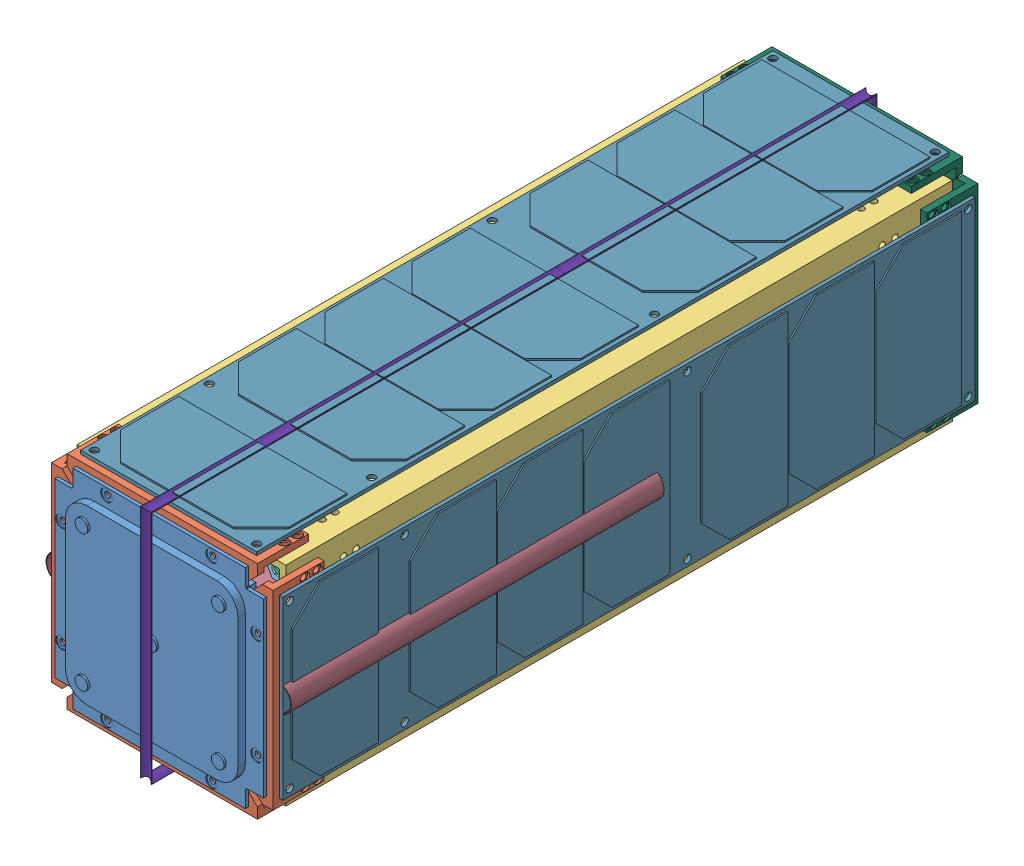
SolidWorks assembly RADIO3, configuration Default. Lengths in mm.
Overall size (115.59 110.69 340.69).
76 component instances, 17 part files, 142 mates.
Components (placement in the parent):
- Nanocom Antenna-1: Nanocom Antenna [Default] at (54.7327 27.087 80.9297) size (98 98 11)
- Top Sipport-1: Top Sipport [Default] at (83.9034 50.4516 80.9297) x (0 -1 0) z (0 0 -1) size (89.4 11 24)
- Top Sipport-2: Top Sipport [Default] at (-15.8818 37.5538 80.9297) x (0 1 0) z (0 0 -1) size (89.4 11 24)
- Top Sipport-3: Top Sipport [Default] at (27.5619 93.8953 80.9297) x (1 0 0) z (0 0 -1) size (89.4 11 24)
- Top Sipport-4: Top Sipport [Default] at (40.4598 -5.8899 80.9297) x (-1 0 0) z (0 0 -1) size (89.4 11 24)
- Support-1: Support [Default] at (-14.9892 90.3455 -221.7132) x (0 -1 0) z (1 0 0) size (18 313 15)
- Support-2: Support [Default] at (-12.332 -4.9973 -221.7132) x (1 0 0) z (0 1 0) size (18 313 15)
- Support-3: Support [Default] at (80.3537 93.0027 -221.7132) x (-1 0 0) z (0 -1 0) size (18 313 15)
- Support-4: Support [Default] at (83.0108 -2.3402 -221.7132) x (0 1 0) z (-1 0 0) size (18 313 15)
- Top Plate2-1: Top Plate2 [Default] at (13.317 21.6849 56.9297) x (-1 0 0) z (0 0 -1) size (92 92 23)
- Nut-1: Nut [Default] at (-1.4892 79.5027 56.9297) size (11.55 10 5.32)
- Nut-2: Nut [Default] at (69.5108 8.5027 56.9297) x (0.821931 0.569587 0) z (0 0 1) size (11.55 10 5.32)
- Nut-3: Nut [Default] at (69.5108 79.5027 56.9297) size (11.55 10 5.32)
- Nut-4: Nut [Default] at (-1.4892 8.5027 56.9297) size (11.55 10 5.32)
- Threaded Rod2-1: Threaded Rod2 [Default] at (69.5108 8.5027 -231.0703) size (6.4 7.01 294.26)
- Threaded Rod2-2: Threaded Rod2 [Default] at (-1.4892 8.5027 -231.0703) size (6.4 7.01 294.26)
- Threaded Rod2-3: Threaded Rod2 [Default] at (-1.4892 79.5027 -231.0703) size (6.4 7.01 294.26)
- Threaded Rod2-4: Threaded Rod2 [Default] at (69.5108 79.5027 -231.0703) size (6.4 7.01 294.26)
- Mid Plate-1: Mid Plate [Default] at (4.649 54.0261 25.9297) size (86 86 3)
- Nut-5: Nut [Default] at (-1.4892 8.5027 20.9297) x (0.999286 -0.037791 0) z (0 0 1) size (11.55 10 5.32)
- Nut-6: Nut [Default] at (-1.4892 8.5027 28.9297) size (11.55 10 5.32)
- Nut-7: Nut [Default] at (69.5108 8.5027 28.9297) size (11.55 10 5.32)
- Nut-8: Nut [Default] at (69.5108 8.5027 20.9297) x (0.921379 0.388666 0) z (0 0 1) size (11.55 10 5.32)
- Nut-9: Nut [Default] at (69.5108 79.5027 28.9297) size (11.55 10 5.32)
- Nut-10: Nut [Default] at (-1.4892 79.5027 28.9297) size (11.55 10 5.32)
- Nut-11: Nut [Default] at (69.5108 79.5027 20.9297) x (0.963517 0.267648 0) z (0 0 1) size (11.55 10 5.32)
- Nut-12: Nut [Default] at (-1.4892 79.5027 20.9297) x (0.997929 0.06432 0) z (0 0 1) size (11.55 10 5.32)
- SDR-1: SDR [Default] at (37.1692 34.198 30.9297) size (65 40 16.8)
- TTC Radio-1: TTC Radio [Default] at (48.3672 78.5027 28.9297) x (0 1 0) z (0 0 1) size (19.7 16 5)
- Raspberry Pi-1: Raspberry Pi [Default] at (63.5108 49.6464 -55.0703) size (66 30.48 5)
- TTC Circuit-1: TTC Circuit [Default] at (24.4431 25.9578 10.9297) size (80 50 10)
- Battery-1: Battery [Default] at (21.7415 31.358 -37.0703) size (70.1 42.59 38.1)
- Tape Antenna-3: Tape Antenna [Default] at (-17.3053 44.2096 -97.0703) x (-0.035253 -0.999378 0) z (0 0 1) size (11.67 4.21 175)
- Tape Antenna-4: Tape Antenna [Default] at (85.299 43.4652 -97.0703) x (0.030207 0.999544 0) z (0 0 1) size (11.67 4.21 175)
- Mid Plate-2: Mid Plate [Default] at (4.649 54.0261 7.9297) size (86 86 3)
- Nut-13: Nut [Default] at (-1.4892 8.5027 10.9297) size (11.55 10 5.32)
- Nut-14: Nut [Default] at (69.5108 79.5027 10.9297) size (11.55 10 5.32)
- Nut-15: Nut [Default] at (-1.4892 8.5027 2.9297) size (11.55 10 5.32)
- Nut-16: Nut [Default] at (-1.4892 79.5027 10.9297) size (11.55 10 5.32)
- Nut-17: Nut [Default] at (-1.4892 79.5027 2.9297) size (11.55 10 5.32)
- Nut-18: Nut [Default] at (69.5108 8.5027 2.9297) size (11.55 10 5.32)
- Nut-19: Nut [Default] at (69.5108 8.5027 10.9297) size (11.55 10 5.32)
- Nut-20: Nut [Default] at (69.5108 79.5027 2.9297) size (11.55 10 5.32)
- Mid Plate-3: Mid Plate [Default] at (4.649 54.0261 -40.0703) size (86 86 3)
- Nut-21: Nut [Default] at (69.5108 79.5027 -37.0703) size (11.55 10 5.32)
- Nut-22: Nut [Default] at (-1.4892 8.5027 -40.0703) x (-0.923728 -0.383049 0) z (0 0 -1) size (11.55 10 5.32)
- Nut-23: Nut [Default] at (-1.4892 79.5027 -40.0703) x (-0.923728 -0.383049 0) z (0 0 -1) size (11.55 10 5.32)
- Nut-24: Nut [Default] at (69.5108 8.5027 -37.0703) size (11.55 10 5.32)
- Nut-25: Nut [Default] at (69.5108 79.5027 -40.0703) x (-0.923728 -0.383049 0) z (0 0 -1) size (11.55 10 5.32)
- Nut-26: Nut [Default] at (69.5108 8.5027 -40.0703) x (-0.923728 -0.383049 0) z (0 0 -1) size (11.55 10 5.32)
- Nut-27: Nut [Default] at (-1.4892 8.5027 -37.0703) size (11.55 10 5.32)
- Nut-28: Nut [Default] at (-1.4892 79.5027 -37.0703) size (11.55 10 5.32)
- Nut-29: Nut [Default] at (-1.4892 8.5027 -63.0703) size (11.55 10 5.32)
- Nut-30: Nut [Default] at (69.5108 79.5027 -63.0703) size (11.55 10 5.32)
- Nut-31: Nut [Default] at (69.5108 8.5027 -63.0703) size (11.55 10 5.32)
- Nut-32: Nut [Default] at (-1.4892 8.5027 -55.0703) size (11.55 10 5.32)
- Nut-33: Nut [Default] at (-1.4892 79.5027 -55.0703) size (11.55 10 5.32)
- Nut-34: Nut [Default] at (69.5108 8.5027 -55.0703) size (11.55 10 5.32)
- Nut-35: Nut [Default] at (-1.4892 79.5027 -63.0703) size (11.55 10 5.32)
- Nut-36: Nut [Default] at (69.5108 79.5027 -55.0703) size (11.55 10 5.32)
- Mid Plate-4: Mid Plate [Default] at (4.649 54.0261 -58.0703) size (86 86 3)
- Top Plate2-2: Top Plate2 [Default] at (54.7047 21.6849 -226.0703) size (92 92 23)
- Nut-37: Nut [Default] at (69.5108 8.5027 -226.0703) x (-0.923728 -0.383049 0) z (0 0 -1) size (11.55 10 5.32)
- Nut-38: Nut [Default] at (69.5108 79.5027 -226.0703) x (-0.923728 -0.383049 0) z (0 0 -1) size (11.55 10 5.32)
- Nut-39: Nut [Default] at (-1.4892 8.5027 -226.0703) x (-0.923728 -0.383049 0) z (0 0 -1) size (11.55 10 5.32)
- Nut-40: Nut [Default] at (-1.4892 79.5027 -226.0703) x (-0.923728 -0.383049 0) z (0 0 -1) size (11.55 10 5.32)
- 3U Panel-1: 3U Panel [Default] at (-17.9892 -8.6653 1.9441) x (0 -1 0) z (-1 0 0) size (82.6 325 2.3)
- 3U Panel-5: 3U Panel [Default] at (86.6788 -7.9973 1.9441) x (1 0 0) z (0 -1 0) size (82.6 325 2.3)
- 3U Panel-6: 3U Panel [Default] at (86.0108 96.6707 1.9441) x (0 1 0) z (1 0 0) size (82.6 325 2.3)
- 3U Panel-7: 3U Panel [Default] at (-18.6571 96.0027 1.9441) x (-1 0 0) z (0 1 0) size (82.6 325 2.3)
- Top Support Solar Panel-1: Top Support Solar Panel [Default] at (27.5619 -3.8899 -250.0703) size (89.4 13 24)
- Top Support Solar Panel-2: Top Support Solar Panel [Default] at (81.9034 37.5538 -250.0703) x (0 1 0) z (0 0 1) size (89.4 13 24)
- Top Support Solar Panel-3: Top Support Solar Panel [Default] at (40.4598 91.8953 -250.0703) x (-1 0 0) z (0 0 1) size (89.4 13 24)
- Top Support Solar Panel-4: Top Support Solar Panel [Default] at (-13.8818 50.4516 -250.0703) x (0 -1 0) z (0 0 1) size (89.4 13 24)
- 1U Panel-1: 1U Panel [Default] at (10.1282 49.1305 -250.0703) x (-1 0 0) z (0 0 -1) size (98 98 2.3)
- Undeployed Boom-1: Undeployed Boom [Default] at (33.4698 71.8204 -107.142) x (0 0 -1) z (1 0 0) size (340.69 110.69 5.53)
Mates (geometry in assembly coordinates):
- Coincident1: coincident: circle of Nanocom Antenna-1; circle of Top Sipport-4
- Coincident2: coincident: circle of Nanocom Antenna-1; circle of Top Sipport-4
- Coincident3: coincident: circle of Nanocom Antenna-1; circle of Top Sipport-2
- Coincident4: coincident: circle of Nanocom Antenna-1; circle of Top Sipport-2
- Coincident5: coincident: circle of Nanocom Antenna-1; circle of Top Sipport-3
- Coincident6: coincident: circle of Nanocom Antenna-1; circle of Top Sipport-3
- Coincident7: coincident: circle of Nanocom Antenna-1; circle of Top Sipport-1
- Coincident8: coincident: circle of Nanocom Antenna-1; circle of Top Sipport-1
- Coincident9: coincident: circle of Top Sipport-2; circle of Support-1
- Coincident10: coincident: circle of Top Sipport-3; circle of Support-1
- Coincident11: coincident: circle of Top Sipport-3; circle of Support-3
- Coincident12: coincident: circle of Top Sipport-1; circle of Support-3
- Coincident13: coincident: circle of Top Sipport-2; circle of Support-2
- Coincident14: coincident: circle of Top Sipport-4; circle of Support-2
- Coincident16: coincident: circle of Top Sipport-4; circle of Support-4
- Coincident17: coincident: circle of Top Sipport-1; circle of Support-4
- Coincident20: coincident: circle of Support-1; circle of Top Plate2-1
- Coincident21: coincident: circle of Support-2; circle of Top Plate2-1
- Coincident22: coincident: circle of Top Plate2-1; circle of Nut-3
- Coincident23: coincident: circle of Top Plate2-1; circle of Nut-1
- Coincident24: coincident: circle of Top Plate2-1; circle of Nut-4
- Coincident25: coincident: circle of Top Plate2-1; circle of Nut-2
- Concentric1: concentric: circle of Top Plate2-1; circle of Threaded Rod2-1
- Coincident26: coincident: plane of Nut-2 through (69.5108 8.5027 61.9297) normal (0 0 1); plane of Threaded Rod2-1 through (69.5108 8.5027 61.9297) normal (0 0 1)
- Concentric2: concentric: circle of Top Plate2-1; circle of Threaded Rod2-4
- Coincident27: coincident: plane of Nut-3 through (69.5108 79.5027 61.9297) normal (0 0 1); plane of Threaded Rod2-4 through (69.5108 79.5027 61.9297) normal (0 0 1)
- Concentric3: concentric: circle of Top Plate2-1; circle of Threaded Rod2-2
- Coincident28: coincident: plane of Nut-4 through (-1.4892 8.5027 61.9297) normal (0 0 1); plane of Threaded Rod2-2 through (-1.4892 8.5027 61.9297) normal (0 0 1)
- Concentric4: concentric: circle of Top Plate2-1; circle of Threaded Rod2-3
- Coincident29: coincident: plane of Nut-1 through (-1.4892 79.5027 61.9297) normal (0 0 1); plane of Threaded Rod2-3 through (-1.4892 79.5027 61.9297) normal (0 0 1)
- Concentric5: concentric: circle of Threaded Rod2-4; circle of Mid Plate-1
- Concentric6: concentric: circle of Threaded Rod2-2; circle of Mid Plate-1
- Concentric7: concentric: circle of Threaded Rod2-2; circle of Nut-6
- Coincident30: coincident: plane of Mid Plate-1 through (4.649 54.0261 28.9297) normal (0 0 1); plane of Nut-6 through (-1.4892 8.5027 28.9297) normal (0 0 -1)
- Concentric8: concentric: circle of Threaded Rod2-2; circle of Nut-5
- Coincident31: coincident: plane of Mid Plate-1 through (4.649 54.0261 25.9297) normal (0 0 -1); plane of Nut-5 through (-1.4892 8.5027 25.9297) normal (0 0 1)
- Concentric9: concentric: circle of Threaded Rod2-1; circle of Nut-7
- Coincident32: coincident: plane of Mid Plate-1 through (4.649 54.0261 28.9297) normal (0 0 1); plane of Nut-7 through (69.5108 8.5027 28.9297) normal (0 0 -1)
- Concentric10: concentric: circle of Threaded Rod2-1; circle of Nut-8
- Coincident33: coincident: plane of Mid Plate-1 through (4.649 54.0261 25.9297) normal (0 0 -1); plane of Nut-8 through (69.5108 8.5027 25.9297) normal (0 0 1)
- Concentric11: concentric: circle of Threaded Rod2-4; circle of Nut-9
- Coincident34: coincident: plane of Mid Plate-1 through (4.649 54.0261 28.9297) normal (0 0 1); plane of Nut-9 through (69.5108 79.5027 28.9297) normal (0 0 -1)
- Concentric12: concentric: circle of Threaded Rod2-3; circle of Nut-10
- Coincident35: coincident: plane of Mid Plate-1 through (4.649 54.0261 28.9297) normal (0 0 1); plane of Nut-10 through (-1.4892 79.5027 28.9297) normal (0 0 -1)
- Concentric13: concentric: circle of Threaded Rod2-4; circle of Nut-11
- Coincident36: coincident: plane of Mid Plate-1 through (4.649 54.0261 25.9297) normal (0 0 -1); plane of Nut-11 through (69.5108 79.5027 25.9297) normal (0 0 1)
- Concentric14: concentric: circle of Threaded Rod2-3; circle of Nut-12
- Coincident37: coincident: plane of Mid Plate-1 through (4.649 54.0261 25.9297) normal (0 0 -1); plane of Nut-12 through (-1.4892 79.5027 25.9297) normal (0 0 1)
- Distance1: distance = 25 mm: plane of Mid Plate-1 through (4.649 54.0261 28.9297) normal (0 0 1); plane of Top Plate2-1 through (13.317 21.6849 53.9297) normal (0 0 -1)
- Coincident39: coincident: plane of Mid Plate-1 through (4.649 54.0261 28.9297) normal (0 0 1); plane of SDR-1 through (37.1692 34.198 28.9297) normal (0 0 -1)
- Distance4: distance = 12 mm: line of SDR-1 through (65.0108 16.0027 28.9297) axis (0 1 0); line of Mid Plate-1 through (77.0108 4.0027 28.9297) axis (0 1 0)
- Distance5: distance = 15 mm: line of SDR-1 through (0.0108 16.0027 28.9297) axis (1 0 0); line of Mid Plate-1 through (-5.9892 1.0027 28.9297) axis (1 0 0)
- Coincident46: coincident: plane of Mid Plate-1 through (4.649 54.0261 28.9297) normal (0 0 1); plane of TTC Radio-1 through (48.3672 78.5027 28.9297) normal (0 0 -1)
- Distance8: distance = 20 mm: plane of TTC Radio-1 through (57.0108 78.5027 30.9297) normal (1 0 0); plane of Mid Plate-1 through (77.0108 4.0027 28.9297) normal (1 0 0)
- Distance9: distance = 5 mm: plane of TTC Radio-1 through (48.3672 82.0027 30.9297) normal (0 1 0); line of Mid Plate-1 through (74.0108 87.0027 28.9297) axis (-1 0 0)
- Coincident53: coincident: plane of TTC Circuit-1 through (24.4431 25.9578 10.9297) normal (0 0 -1); plane of Mid Plate-2 through (4.649 54.0261 10.9297) normal (0 0 1)
- Distance10: distance = 5 mm: line of TTC Circuit-1 through (-4.4066 66.0027 12.9297) axis (0 -1 0); line of Mid Plate-2 through (-8.9892 84.0027 10.9297) axis (0 -1 0)
- Distance13: distance = 21.095 mm: line of TTC Circuit-1 through (75.5934 66.0027 12.9297) axis (-1 0 0); line of Mid Plate-2 through (74.0108 87.0027 10.9297) axis (-1 0 0)
- Concentric16: concentric: circle of Threaded Rod2-2; circle of Mid Plate-2
- Concentric18: concentric: circle of Threaded Rod2-4; circle of Mid Plate-2
- Concentric19: concentric: circle of Threaded Rod2-4; circle of Nut-14
- Coincident59: coincident: plane of Mid Plate-2 through (4.649 54.0261 10.9297) normal (0 0 1); plane of Nut-14 through (69.5108 79.5027 10.9297) normal (0 0 -1)
- Concentric20: concentric: circle of Threaded Rod2-4; circle of Nut-20
- Coincident60: coincident: plane of Mid Plate-2 through (4.649 54.0261 7.9297) normal (0 0 -1); plane of Nut-20 through (69.5108 79.5027 7.9297) normal (0 0 1)
- Concentric21: concentric: circle of Threaded Rod2-1; circle of Nut-19
- Coincident61: coincident: plane of Mid Plate-2 through (4.649 54.0261 10.9297) normal (0 0 1); plane of Nut-19 through (69.5108 8.5027 10.9297) normal (0 0 -1)
- Concentric22: concentric: circle of Threaded Rod2-1; circle of Nut-18
- Coincident62: coincident: plane of Mid Plate-2 through (4.649 54.0261 7.9297) normal (0 0 -1); plane of Nut-18 through (69.5108 8.5027 7.9297) normal (0 0 1)
- Concentric23: concentric: circle of Threaded Rod2-2; circle of Nut-13
- Coincident63: coincident: plane of Mid Plate-2 through (4.649 54.0261 10.9297) normal (0 0 1); plane of Nut-13 through (-1.4892 8.5027 10.9297) normal (0 0 -1)
- Concentric24: concentric: circle of Threaded Rod2-2; circle of Nut-15
- Coincident64: coincident: plane of Mid Plate-2 through (4.649 54.0261 7.9297) normal (0 0 -1); plane of Nut-15 through (-1.4892 8.5027 7.9297) normal (0 0 1)
- Concentric25: concentric: circle of Threaded Rod2-3; circle of Nut-16
- Coincident65: coincident: plane of Mid Plate-2 through (4.649 54.0261 10.9297) normal (0 0 1); plane of Nut-16 through (-1.4892 79.5027 10.9297) normal (0 0 -1)
- Concentric26: concentric: circle of Threaded Rod2-3; circle of Nut-17
- Coincident66: coincident: plane of Mid Plate-2 through (4.649 54.0261 7.9297) normal (0 0 -1); plane of Nut-17 through (-1.4892 79.5027 7.9297) normal (0 0 1)
- Distance14: distance = 15 mm: plane of Mid Plate-2 through (4.649 54.0261 10.9297) normal (0 0 1); plane of Mid Plate-1 through (4.649 54.0261 25.9297) normal (0 0 -1)
- Coincident68: coincident: circle of Mid Plate-3; circle of Nut-21
- Coincident69: coincident: circle of Mid Plate-3; circle of Nut-24
- Coincident70: coincident: circle of Mid Plate-3; circle of Nut-27
- Coincident71: coincident: circle of Mid Plate-3; circle of Nut-28
- Coincident72: coincident: circle of Mid Plate-3; circle of Nut-25
- Coincident73: coincident: circle of Mid Plate-3; circle of Nut-23
- Coincident74: coincident: circle of Mid Plate-3; circle of Nut-22
- Coincident76: coincident: circle of Mid Plate-3; circle of Nut-26
- Coincident77: coincident: plane of Battery-1 through (21.7415 31.358 -37.0703) normal (0 0 -1); plane of Mid Plate-3 through (4.649 54.0261 -37.0703) normal (0 0 1)
- Distance16: distance = 30 mm: line of Battery-1 through (57.8687 57.4223 -32.0703) axis (-1 0 0); line of Mid Plate-3 through (74.0108 87.0027 -37.0703) axis (-1 0 0)
- Distance17: distance = 15 mm: line of Battery-1 through (62.8687 24.8323 -32.0703) axis (0 1 0); line of Mid Plate-3 through (77.0108 4.0027 -37.0703) axis (0 1 0)
- Concentric27: concentric: circle of Threaded Rod2-2; circle of Nut-27
- Concentric28: concentric: circle of Threaded Rod2-4; circle of Nut-21
- Distance18: distance = 45 mm: plane of Mid Plate-3 through (4.649 54.0261 -37.0703) normal (0 0 1); plane of Mid Plate-2 through (4.649 54.0261 7.9297) normal (0 0 -1)
- Coincident83: coincident: plane of Raspberry Pi-1 through (63.5108 49.6464 -55.0703) normal (0 0 -1); plane of Mid Plate-4 through (4.649 54.0261 -55.0703) normal (0 0 1)
- Distance19: distance = 30 mm: line of Raspberry Pi-1 through (67.0108 57.0027 -55.0703) axis (-1 0 0); line of Mid Plate-4 through (74.0108 87.0027 -55.0703) axis (-1 0 0)
- Distance20: distance = 10 mm: line of Raspberry Pi-1 through (67.0108 26.5227 -55.0703) axis (0 1 0); line of Mid Plate-4 through (77.0108 4.0027 -55.0703) axis (0 1 0)
- Concentric29: concentric: circle of Nut-29; circle of Mid Plate-4
- Coincident87: coincident: plane of Nut-29 through (-1.4892 8.5027 -58.0703) normal (0 0 1); plane of Mid Plate-4 through (4.649 54.0261 -58.0703) normal (0 0 -1)
- Concentric30: concentric: circle of Nut-31; circle of Mid Plate-4
- Coincident89: coincident: plane of Nut-31 through (69.5108 8.5027 -58.0703) normal (0 0 1); plane of Mid Plate-4 through (4.649 54.0261 -58.0703) normal (0 0 -1)
- Concentric31: concentric: circle of Nut-30; circle of Mid Plate-4
- Coincident91: coincident: plane of Nut-30 through (69.5108 79.5027 -58.0703) normal (0 0 1); plane of Mid Plate-4 through (4.649 54.0261 -58.0703) normal (0 0 -1)
- Concentric32: concentric: circle of Nut-35; circle of Mid Plate-4
- Coincident93: coincident: plane of Nut-35 through (-1.4892 79.5027 -58.0703) normal (0 0 1); plane of Mid Plate-4 through (4.649 54.0261 -58.0703) normal (0 0 -1)
- Coincident94: coincident: circle of Nut-33; circle of Mid Plate-4
- Coincident95: coincident: circle of Nut-32; circle of Mid Plate-4
- Coincident96: coincident: circle of Nut-36; circle of Mid Plate-4
- Coincident97: coincident: circle of Nut-34; circle of Mid Plate-4
- Concentric33: concentric: circle of Threaded Rod2-2; circle of Nut-29
- Concentric34: concentric: circle of Threaded Rod2-3; circle of Nut-35
- Distance21: distance = 15 mm: plane of Mid Plate-4 through (4.649 54.0261 -55.0703) normal (0 0 1); plane of Mid Plate-3 through (4.649 54.0261 -40.0703) normal (0 0 -1)
- Coincident100: coincident: circle of Top Plate2-2; circle of Nut-37
- Coincident101: coincident: circle of Top Plate2-2; circle of Nut-39
- Coincident102: coincident: circle of Top Plate2-2; circle of Nut-38
- Coincident103: coincident: circle of Top Plate2-2; circle of Nut-40
- Concentric35: concentric: circle of Threaded Rod2-3; circle of Top Plate2-2
- Concentric36: concentric: circle of Threaded Rod2-4; circle of Top Plate2-2
- Coincident104: coincident: plane of Threaded Rod2-4 through (69.5108 79.5027 -231.0703) normal (0 0 -1); plane of Nut-38 through (69.5108 79.5027 -231.0703) normal (0 0 -1)
- Coincident123: coincident: circle of Top Sipport-2; circle of 3U Panel-1
- Coincident124: coincident: circle of Top Sipport-2; circle of 3U Panel-1
- Coincident125: coincident: circle of Top Sipport-4; circle of 3U Panel-5
- Coincident126: coincident: circle of Top Sipport-4; circle of 3U Panel-5
- Coincident127: coincident: circle of Top Sipport-3; circle of 3U Panel-7
- Coincident128: coincident: circle of Top Sipport-3; circle of 3U Panel-7
- Coincident129: coincident: circle of Top Sipport-1; circle of 3U Panel-6
- Coincident130: coincident: circle of Top Sipport-1; circle of 3U Panel-6
- Coincident131: coincident: point of Tape Antenna-4; line of 3U Panel-6 through (87.6108 85.3027 77.9297) axis (0 -1 0)
- Coincident132: coincident: point of Tape Antenna-4; line of 3U Panel-6 through (87.6108 85.3027 77.9297) axis (0 -1 0)
- Parallel16: parallel: line of Support-4 through (83.0108 -4.9973 -241.0703) axis (0 0 1); line of Tape Antenna-4 through (87.7209 37.6494 77.9297) axis (0 0 -1)
- Coincident137: coincident: point of Tape Antenna-3; line of 3U Panel-1 through (-19.5892 2.7027 77.9297) axis (0 1 0)
- Coincident138: coincident: point of Tape Antenna-3; line of 3U Panel-1 through (-19.5892 2.7027 77.9297) axis (0 1 0)
- Parallel19: parallel: line of Tape Antenna-3 through (-19.6978 50.0375 77.9297) axis (0 0 -1); line of 3U Panel-1 through (-19.5892 85.3027 77.9297) axis (0 0 -1)
- Coincident140: coincident: circle of 3U Panel-6; circle of Top Support Solar Panel-2
- Coincident141: coincident: circle of 3U Panel-6; circle of Top Support Solar Panel-2
- Coincident142: coincident: circle of 3U Panel-5; circle of Top Support Solar Panel-1
- Coincident143: coincident: circle of 3U Panel-5; circle of Top Support Solar Panel-1
- Coincident144: coincident: circle of 3U Panel-1; circle of Top Support Solar Panel-4
- Coincident145: coincident: circle of 3U Panel-1; circle of Top Support Solar Panel-4
- Coincident146: coincident: circle of 3U Panel-7; circle of Top Support Solar Panel-3
- Coincident147: coincident: circle of 3U Panel-7; circle of Top Support Solar Panel-3
- Coincident148: coincident: circle of Top Support Solar Panel-3; circle of 1U Panel-1
- Coincident149: coincident: circle of Top Support Solar Panel-1; circle of 1U Panel-1
- Distance23: distance = 1 mm: plane of 1U Panel-1 through (10.1282 49.1305 -250.0703) normal (0 0 1); cylinder of Undeployed Boom-1 through (33.4698 99.1786 -254.7556) axis (0 -1 0) radius 3.6853
- Parallel20: parallel: line of Support-3 through (83.0108 93.0027 -241.0703) axis (0 0 1); line of Undeployed Boom-1 through (30.7418 98.7657 -108.142) axis (0 0 -1)
